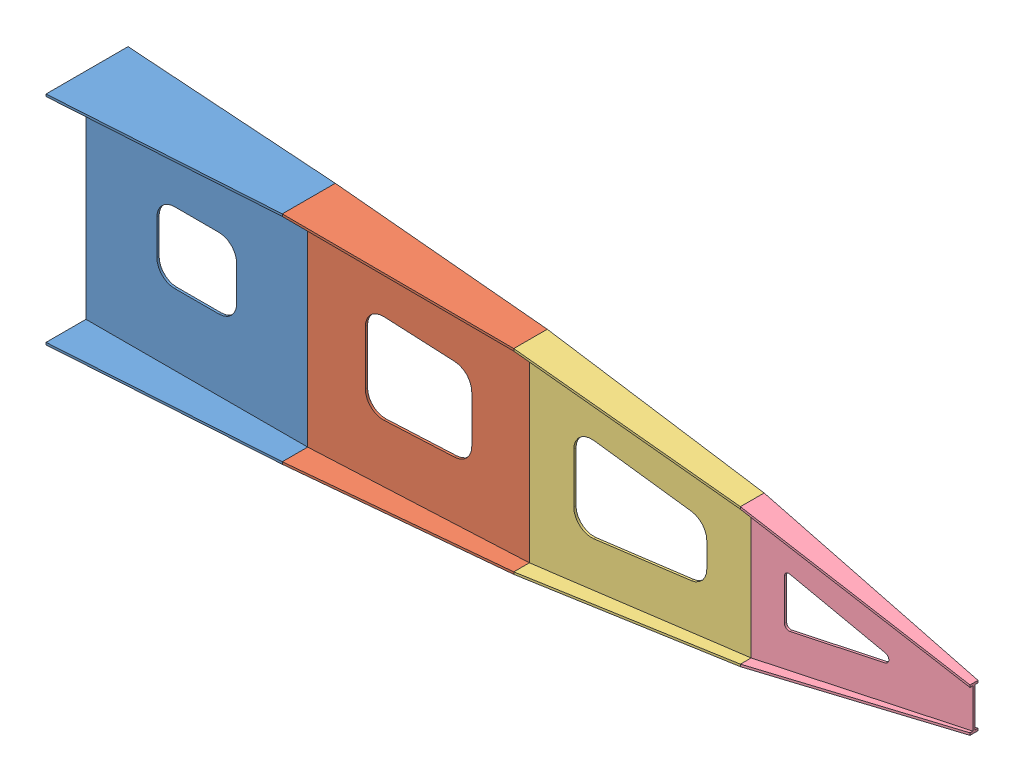
SolidWorks assembly 1.30 tolerance assembly, configuration Default. Lengths in mm.
Overall size (4000 980 370).
4 component instances, 4 part files, 9 mates.
Components (placement in the parent):
- 1-1: 1 [Default] at (-775.9263 612.0858 1043.8579) size (1000 980 370)
- 2-2: 2 [Default] at (224.0737 612.0858 1043.8579) size (1000 978 239)
- 3-2: 3 [Default] at (1224.0737 612.0858 1043.8579) size (1000 882 151)
- 4-2: 4 [Default] at (2224.0737 612.0858 1043.8579) size (1000 625 107)
Mates (geometry in assembly coordinates):
- Coincident39: coincident anti-aligned: plane of 1-1 through (224.0737 612.0858 1043.8579) normal (1 0 0); plane of 2-2 through (224.0737 612.0858 1043.8579) normal (-1 0 0)
- Coincident40: coincident anti-aligned: plane of 2-2 through (1224.0737 612.0858 1043.8579) normal (1 0 0); plane of 3-2 through (1224.0737 612.0858 1043.8579) normal (-1 0 0)
- Coincident42: coincident: point of 1-1; point of 2-2
- Coincident43: coincident: point of 1-1; point of 2-2
- Coincident44: coincident: point of 2-2; point of 3-2
- Coincident46: coincident: point of 2-2; point of 3-2
- Coincident49: coincident: point of 3-2; point of 4-2
- Coincident52: coincident aligned: plane of 3-2 through (1224.0737 612.0858 1053.8579) normal (0 0 1); plane of 4-2 through (2224.0737 612.0858 1053.8579) normal (0 0 1)
- Coincident53: coincident: point of 3-2; point of 4-2
